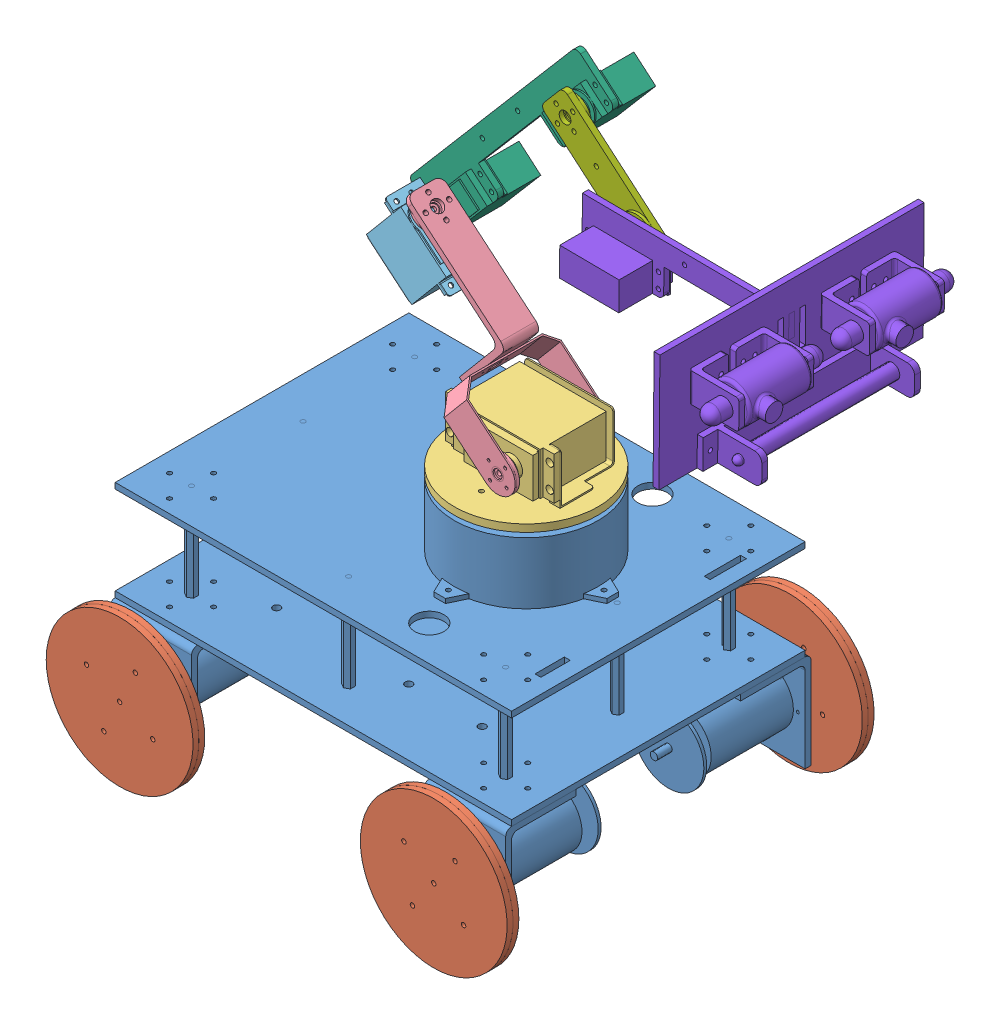
SolidWorks assembly exa_robot_part - Copy, configuration Default. Lengths in mm.
Overall size (452.74 461.66 342.18).
11 component instances, 8 part files, 26 mates.
Components (placement in the parent):
- base_robot-1: base_robot [Default] at (14.2374 -23.114 -6.4589) size (270 179.13 234)
- roda_robot_fix-1: roda_robot_fix [Default] at (268.1239 -5.9891 251.6556) x (0.408711 0.912664 0) z (0 0 1) size (100 100 21)
- roda_robot_fix-2: roda_robot_fix [Default] at (-22.1829 120.8673 251.6556) x (-0.2415 -0.970401 0) z (0 0 1) size (100 100 21)
- roda_robot_fix-3: roda_robot_fix [Default] at (-43.3679 96.894 162.7099) x (0.933321 0.359042 0) z (0 0 -1) size (100 100 21)
- roda_robot_fix-4: roda_robot_fix [Default] at (229.5868 134.8934 162.7099) x (0.816348 -0.57756 0) z (0 0 -1) size (100 100 21)
- link1_robot-1: link1_robot [Default] at (14.2374 -23.114 -6.4589) size (98 43 98)
- link2_robot-1: link2_robot [Default] at (14.2374 -23.114 -6.4589) size (99.47 123.93 66)
- link3_robot-1: link3_robot [Default] at (14.2374 -23.114 -6.4589) size (56.44 54.96 29)
- link4_robot-1: link4_robot [Default] at (11.4345 -22.4006 -6.4589) x (0.999966 -0.008267 0) z (0 0 1) size (137.73 155 42.35)
- link5_robot-1: link5_robot [Default] at (11.4345 -22.4006 -6.4589) x (0.999966 -0.008267 0) z (0 0 1) size (81.1 72.97 14)
- link6_eof_robot-1: link6_eof_robot [Default] at (11.4345 -22.4006 -6.4589) x (0.999966 -0.008267 0) z (0 0 1) size (184.63 80 180)
Mates (geometry in assembly coordinates):
- Coincident1: coincident anti-aligned: plane of base_robot-1 through (258.5015 16.6149 311.1827) normal (0 0 1); plane of roda_robot_fix-1 through (235.6028 60.827 311.1827) normal (0 0 -1)
- Concentric1: concentric aligned: cylinder of base_robot-1 through (235.6028 60.827 324.1827) axis (0 0 -1) radius 2.5; cylinder of roda_robot_fix-1 through (235.6028 60.827 324.1827) axis (0 0 -1) radius 2.5
- Concentric2: concentric aligned: cylinder of base_robot-1 through (235.6028 60.827 90.1827) axis (0 0 1) radius 2.5; cylinder of roda_robot_fix-4 through (235.6028 60.827 90.1827) axis (0 0 1) radius 2.5
- Coincident3: coincident anti-aligned: plane of base_robot-1 through (212.704 16.6149 103.1827) normal (0 0 -1); plane of roda_robot_fix-4 through (235.6028 60.827 103.1827) normal (0 0 1)
- Coincident4: coincident anti-aligned: plane of base_robot-1 through (-1.296 105.0391 311.1827) normal (0 0 1); plane of roda_robot_fix-2 through (21.6028 60.827 311.1827) normal (0 0 -1)
- Concentric3: concentric aligned: cylinder of base_robot-1 through (21.6028 60.827 324.1827) axis (0 0 -1) radius 2.5; cylinder of roda_robot_fix-2 through (21.6028 60.827 324.1827) axis (0 0 -1) radius 2.5
- Coincident5: coincident anti-aligned: plane of base_robot-1 through (-1.296 16.6149 103.1827) normal (0 0 -1); plane of roda_robot_fix-3 through (21.6028 60.827 103.1827) normal (0 0 1)
- Concentric4: concentric aligned: cylinder of base_robot-1 through (21.6028 60.827 90.1827) axis (0 0 1) radius 2.5; cylinder of roda_robot_fix-3 through (21.6028 60.827 90.1827) axis (0 0 1) radius 2.5
- Coincident6: coincident anti-aligned: plane of base_robot-1 through (183.8898 208.9523 217.0887) normal (0 1 0); plane of link1_robot-1 through (173.6028 208.9523 207.1827) normal (0 -1 0)
- Concentric5: concentric aligned: cylinder of base_robot-1 through (173.6028 189.6967 207.1827) axis (0 1 0) radius 2.8131; cylinder of link1_robot-1 through (173.6028 204.9523 207.1827) axis (0 1 0) radius 3
- Coincident7: coincident anti-aligned: plane of link1_robot-1 through (189.1028 233.9523 239.1727) normal (0 0 1); plane of link2_robot-1 through (189.1028 233.9523 239.1727) normal (0 0 -1)
- Concentric6: concentric anti-aligned: cylinder of link1_robot-1 through (189.1028 233.9523 239.1727) axis (0 0 -1) radius 3; cylinder of link2_robot-1 through (189.1028 233.9523 236.1727) axis (0 0 1) radius 3
- Concentric7: concentric anti-aligned: cylinder of link2_robot-1 through (108.8974 331.277 208.7585) axis (0.642788 0.766044 0) radius 3; cylinder of link3_robot-1 through (110.8257 333.5751 208.7585) axis (-0.642788 -0.766044 0) radius 2.9972
- Coincident9: coincident anti-aligned: plane of link2_robot-1 through (110.8257 333.5751 208.7585) normal (-0.642788 -0.766044 0); plane of link3_robot-1 through (110.8257 333.5751 208.7585) normal (0.642788 0.766044 0)
- Coincident10: coincident anti-aligned: plane of link3_robot-1 through (99.1297 316.2635 192.7915) normal (0 0 -1); plane of link4_robot-1 through (99.1297 316.2635 192.7915) normal (0 0 1)
- Concentric8: concentric anti-aligned: cylinder of link3_robot-1 through (99.1297 316.2635 189.7915) axis (0 0 1) radius 3; cylinder of link4_robot-1 through (99.1297 316.2635 192.7915) axis (0 0 -1) radius 2.9972
- Coincident11: coincident anti-aligned: plane of link4_robot-1 through (191.6635 423.9248 192.7915) normal (0 0 1); plane of link5_robot-1 through (191.6635 423.9248 192.7915) normal (0 0 -1)
- Concentric9: concentric anti-aligned: cylinder of link4_robot-1 through (191.6635 423.9248 192.7915) axis (0 0 -1) radius 2.9972; cylinder of link5_robot-1 through (191.6635 423.9248 189.7915) axis (0 0 1) radius 3
- Coincident12: coincident anti-aligned: plane of link5_robot-1 through (241.87 381.0843 200.7915) normal (0 0 1); plane of link6_eof_robot-1 through (241.87 381.0843 200.7915) normal (0 0 -1)
- Concentric10: concentric anti-aligned: cylinder of link5_robot-1 through (241.87 381.0843 203.7915) axis (0 0 -1) radius 3; cylinder of link6_eof_robot-1 through (241.87 381.0843 200.7915) axis (0 0 1) radius 2.9972
- LimitAngle1: limit planar angle = 2.443461 rad anti-aligned: plane of link1_robot-1 through (173.6028 213.9523 207.1827) normal (0 1 0); plane of link2_robot-1 through (166.9546 268.2017 195.8793) normal (0.642788 0.766044 0)
- LimitAngle2: limit planar angle = 1.570796 rad anti-aligned: plane of link3_robot-1 through (93.6106 327.8772 218.7915) normal (-0.766044 0.642788 0); plane of link2_robot-1 through (109.4871 290.3828 220.7585) normal (0 0 1)
- LimitAngle3: limit planar angle = 1.562529 rad aligned: plane of link4_robot-1 through (100.5792 302.5054 177.361) normal (-0.649099 -0.760704 0); plane of link3_robot-1 through (93.6106 327.8772 218.7915) normal (-0.766044 0.642788 0)
- LimitAngle4: limit planar angle = 0 rad aligned: plane of link4_robot-1 through (190.214 437.683 177.361) normal (0.649099 0.760704 0); plane of link5_robot-1 through (190.3243 440.8425 198.7915) normal (0.649099 0.760704 0)
- LimitAngle5: limit planar angle = 2.268928 rad anti-aligned: plane of link5_robot-1 through (174.7459 422.5856 198.7915) normal (-0.649099 -0.760704 0); plane of link6_eof_robot-1 through (224.6686 374.3358 216.222) normal (-0.999966 0.008267 0)
- LimitAngle9: limit planar angle = 1.570796 rad anti-aligned: plane of link1_robot-1 through (203.1028 247.9523 225.1827) normal (1 0 0); plane of base_robot-1 through (200.3661 159.827 307.1827) normal (0 0 1)
